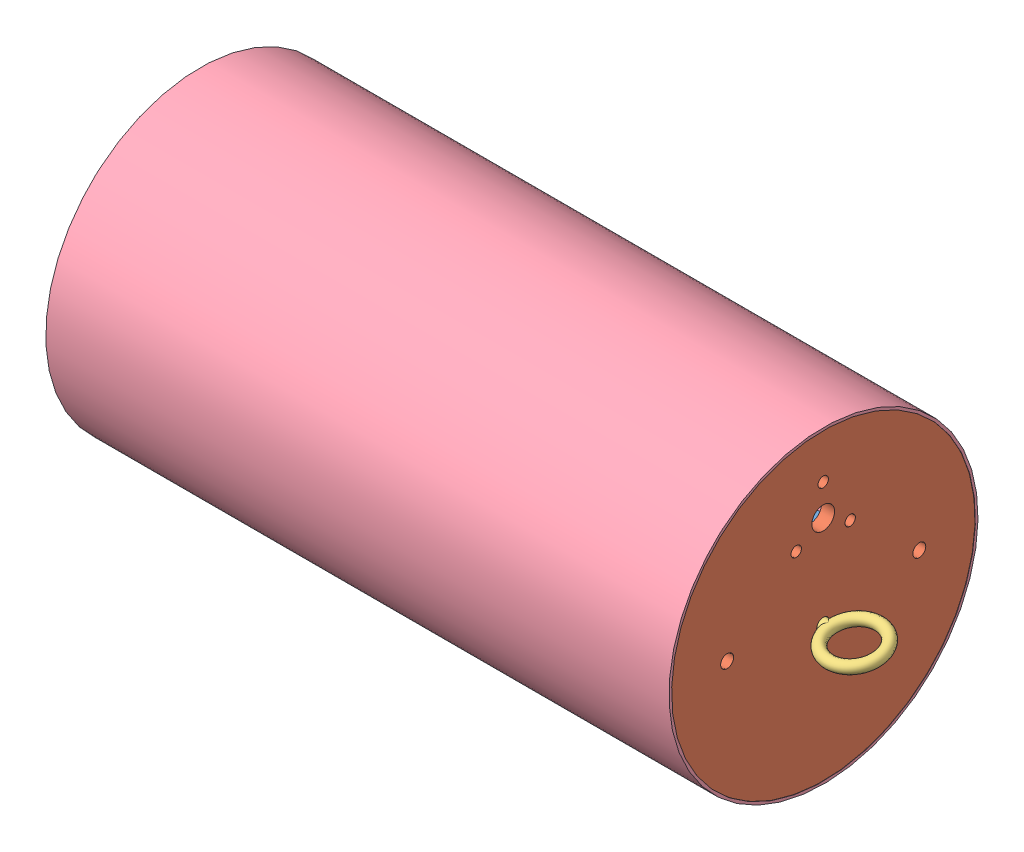
SolidWorks assembly E-Bay, configuration Default. Lengths in mm.
Overall size (371.61 213.58 213.58).
6 component instances, 4 part files, 9 mates.
Components (placement in the parent):
- Ebay_Sled-1: Ebay_Sled [默认] at (145.8707 106.0415 226.1531) size (292.1 29.84 139.7)
- EndCap-1: EndCap [默认] at (-0.1793 110.804 226.1531) x (0 0 1) z (0 -1 0) size (148.59 6.35 148.59)
- EndCap-2: EndCap [默认] at (291.9207 110.804 226.1531) x (0 0 -1) z (0 -1 0) size (148.59 6.35 148.59)
- Ebay_Eyebolt-1: Ebay_Eyebolt [Default] at (-27.9923 102.676 226.1531) size (55.31 6.35 30.16)
- Ebay_Eyebolt-2: Ebay_Eyebolt [Default] at (313.4574 102.676 226.1531) x (-1 0 0) z (0 0.166604 -0.986024) size (55.31 6.35 30.16)
- shell-1: shell [默认] at (298.4219 110.804 226.1531) x (0 0.733351 0.67985) z (0 -0.67985 0.733351) size (151.13 304.8 151.13)
Mates (geometry in assembly coordinates):
- Concentric2: concentric aligned: cylinder of Ebay_Sled-1 through (9.3457 110.804 273.1431) axis (-1 0 0) radius 3.175; cylinder of EndCap-1 through (8.8009 110.804 273.1431) axis (-1 0 0) radius 3.175
- Concentric3: concentric aligned: cylinder of Ebay_Sled-1 through (9.3457 110.804 179.1631) axis (-1 0 0) radius 3.175; cylinder of EndCap-1 through (8.8009 110.804 179.1631) axis (-1 0 0) radius 3.175
- Coincident3: coincident aligned: circle of Ebay_Sled-1; circle of EndCap-1
- Concentric4: concentric aligned: cylinder of Ebay_Sled-1 through (282.3957 110.804 179.1631) axis (1 0 0) radius 3.175; cylinder of EndCap-2 through (282.9404 110.804 179.1631) axis (1 0 0) radius 3.175
- Concentric5: concentric aligned: cylinder of Ebay_Sled-1 through (282.3957 110.804 273.1431) axis (1 0 0) radius 3.175; cylinder of EndCap-2 through (282.9404 110.804 273.1431) axis (1 0 0) radius 3.175
- Coincident4: coincident anti-aligned: circle of Ebay_Sled-1; circle of EndCap-2
- Concentric6: concentric aligned: cylinder of EndCap-1 through (8.8009 102.676 226.1531) axis (-1 0 0) radius 3.175; cylinder of Ebay_Eyebolt-1 through (-3.3861 102.676 226.1531) axis (-1 0 0) radius 3.175
- Concentric7: concentric aligned: cylinder of EndCap-2 through (282.9404 102.676 226.1531) axis (1 0 0) radius 3.175; cylinder of Ebay_Eyebolt-2 through (288.8511 102.676 226.1531) axis (1 0 0) radius 3.175
- Concentric8: concentric aligned: cylinder of EndCap-1 through (-6.5293 110.804 226.1531) axis (1 0 0) radius 74.295; cylinder of shell-1 through (-6.3781 110.804 226.1531) axis (1 0 0) radius 74.295
